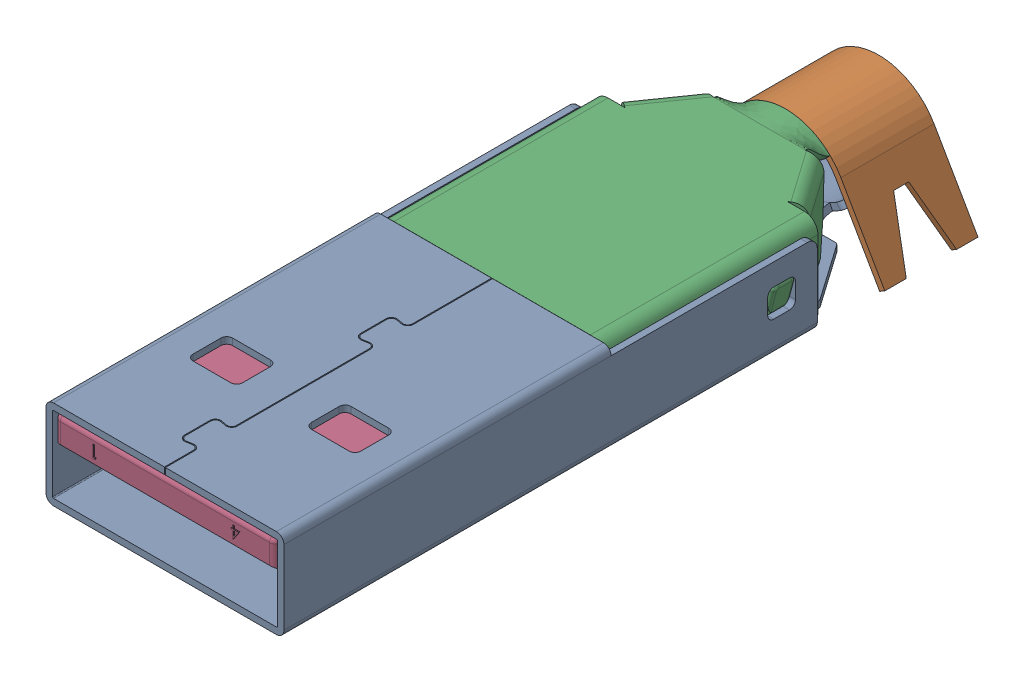
SolidWorks assembly 1AA05-003_1AA05-007, configuration Default. Lengths in mm.
Overall size (12 5.78 36.48).
8 component instances, 5 part files, 0 mates.
Components (placement in the parent):
- 1AA05-003-MA1-1: 1AA05-003-MA1 [Default] at origin size (12 4.61 36.43)
- 1AA05-003-MA2_SM CABLE DIA-1: 1AA05-003-MA2_SM CABLE DIA [Default] at (0 0 -16.5) x (-1 0 0) z (0 0 1) size (11.93 5.78 19.5)
- 1AA05-003-MA3-1: 1AA05-003-MA3 [Default] at (0 0 -8.6) x (-1 0 0) z (0 0 1) size (11.15 3.8 22.3)
- 1AA05-003-MA4-1: 1AA05-003-MA4 [Default] at (3.5 0.75 -1.6002) x (-1 0 0) z (0 0 1) size (1.27 0.76 18.42)
- 1AA05-003-MA4-2: 1AA05-003-MA4 [Default] at (1 0.75 -2.667) x (-1 0 0) z (0 0 1) size (1.27 0.76 18.42)
- 1AA05-003-MA4-3: 1AA05-003-MA4 [Default] at (-1 0.75 -2.667) x (-1 0 0) z (0 0 1) size (1.27 0.76 18.42)
- 1AA05-003-MA4-4: 1AA05-003-MA4 [Default] at (-3.5 0.75 -1.6002) x (-1 0 0) z (0 0 1) size (1.27 0.76 18.42)
- 1AA05-003-MA5-1: 1AA05-003-MA5 [Default] at (0 1.85 -22.45) x (-1 0 0) z (0 0 1) size (10.5 3.75 7)
